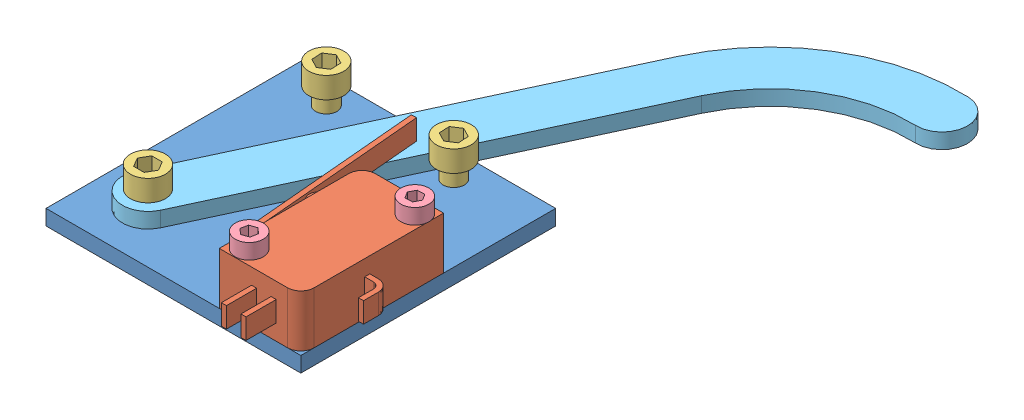
SolidWorks assembly switch_trigger, configuration Default. Lengths in mm.
Overall size (81.04 17 122.36).
8 component instances, 5 part files, 16 mates.
Components (placement in the parent):
- base_plate-1: base_plate [Default] at (-27.428 4.2139 22.3993) size (50 3 50)
- lever_microswitch-1: lever_microswitch [Default] at (22.572 12.3139 -5.6007) x (0 0 1) z (0 -1 0) size (50.6 26.9 10.2)
- simplified_8-32_socket_head_cap_screw-1: simplified_8-32_socket_head_cap_screw [0.25] at (-17.428 10.5639 12.3993) size (6.86 10.52 6.86)
- simplified_M3_socket_head_cap_screw-1: simplified_M3_socket_head_cap_screw [M3 x 14] at (9.5738 17.4139 19.5253) x (0.189271 0 -0.981925) z (0.981925 0 0.189271) size (5.5 17 5.5)
- simplified_M3_socket_head_cap_screw-2: simplified_M3_socket_head_cap_screw [M3 x 14] at (19.8738 17.4139 -2.6747) x (0.470566 0 -0.882365) z (0.882365 0 0.470566) size (5.5 17 5.5)
- simplified_8-32_socket_head_cap_screw-3: simplified_8-32_socket_head_cap_screw [0.25] at (-17.428 10.5639 -22.6007) x (0.890093 0 0.455779) z (-0.455779 0 0.890093) size (6.86 10.52 6.86)
- simplified_8-32_socket_head_cap_screw-4: simplified_8-32_socket_head_cap_screw [0.25] at (7.572 10.5639 -22.6007) x (0.890093 0 0.455779) z (-0.455779 0 0.890093) size (6.86 10.52 6.86)
- switch_lever-1: switch_lever [Default] at (-17.428 7.2139 12.3993) x (0.420492 0 -0.907296) z (0.907296 0 0.420492) size (120 3 30)
Mates (geometry in assembly coordinates):
- Coincident1: coincident anti-aligned: plane of base_plate-1 through (-27.428 7.2139 22.3993) normal (0 1 0); plane of lever_microswitch-1 through (19.9903 7.2139 19.8175) normal (0 -1 0)
- Coincident2: coincident aligned: plane of base_plate-1 through (22.572 7.2139 22.3993) normal (1 0 0); plane of lever_microswitch-1 through (22.572 7.2139 -5.6007) normal (1 0 0)
- Coincident3: coincident aligned: plane of base_plate-1 through (-27.428 7.2139 22.3993) normal (0 0 1); plane of lever_microswitch-1 through (19.9903 7.2139 22.3993) normal (0 0 1)
- Concentric1: concentric anti-aligned: cylinder of lever_microswitch-1 through (9.5738 17.4139 19.5253) axis (0 -1 0) radius 1.5; cylinder of simplified_M3_socket_head_cap_screw-1 through (9.5738 27.3211 19.5253) axis (0 1 0) radius 1.5
- Coincident4: coincident anti-aligned: plane of lever_microswitch-1 through (19.9903 17.4139 19.8175) normal (0 1 0); plane of simplified_M3_socket_head_cap_screw-1 through (10.0943 17.4139 16.825) normal (0 -1 0)
- Tangent1: tangent anti-aligned: plane of lever_microswitch-1 through (18.3738 17.4139 -2.8747) normal (1 0 0); cylinder of simplified_M3_socket_head_cap_screw-2 through (19.8738 27.3211 -2.6747) axis (0 1 0) radius 1.5
- Coincident6: coincident anti-aligned: plane of lever_microswitch-1 through (19.9903 17.4139 19.8175) normal (0 1 0); plane of simplified_M3_socket_head_cap_screw-2 through (21.1678 17.4139 -5.1012) normal (0 -1 0)
- Concentric2: concentric aligned: cylinder of base_plate-1 through (-17.428 4.2139 12.3993) axis (0 1 0) radius 2.0066; cylinder of simplified_8-32_socket_head_cap_screw-1 through (-17.428 20.4711 12.3993) axis (0 1 0) radius 2.0828
- Coincident7: coincident aligned: plane of base_plate-1 through (-27.428 4.2139 22.3993) normal (0 -1 0); plane of simplified_8-32_socket_head_cap_screw-1 through (-15.3452 4.2139 12.3993) normal (0 -1 0)
- Concentric5: concentric aligned: cylinder of base_plate-1 through (-17.428 4.2139 -22.6007) axis (0 1 0) radius 2.0066; cylinder of simplified_8-32_socket_head_cap_screw-3 through (-17.428 20.4711 -22.6007) axis (0 1 0) radius 2.0828
- Coincident9: coincident aligned: plane of base_plate-1 through (-27.428 4.2139 22.3993) normal (0 -1 0); plane of simplified_8-32_socket_head_cap_screw-3 through (-15.5741 4.2139 -21.6515) normal (0 -1 0)
- Concentric6: concentric aligned: cylinder of base_plate-1 through (7.572 4.2139 -22.6007) axis (0 1 0) radius 2.0066; cylinder of simplified_8-32_socket_head_cap_screw-4 through (7.572 20.4711 -22.6007) axis (0 1 0) radius 2.0828
- Coincident10: coincident aligned: plane of base_plate-1 through (-27.428 4.2139 22.3993) normal (0 -1 0); plane of simplified_8-32_socket_head_cap_screw-4 through (9.4259 4.2139 -21.6515) normal (0 -1 0)
- Coincident12: coincident anti-aligned: axis of lever_microswitch-1 through (19.8738 17.4139 -2.6747) axis (0 -1 0); axis of simplified_M3_socket_head_cap_screw-2 through (19.8738 3.4139 -2.6747) axis (0 1 0)
- Concentric8: concentric aligned: cylinder of base_plate-1 through (-17.428 4.2139 12.3993) axis (0 1 0) radius 2.0066; cylinder of switch_lever-1 through (-17.428 7.2129 12.3993) axis (0 1 0) radius 2.159
- Coincident13: coincident anti-aligned: plane of base_plate-1 through (-27.428 7.2139 22.3993) normal (0 1 0); plane of switch_lever-1 through (-17.428 7.2139 12.3993) normal (0 -1 0)
